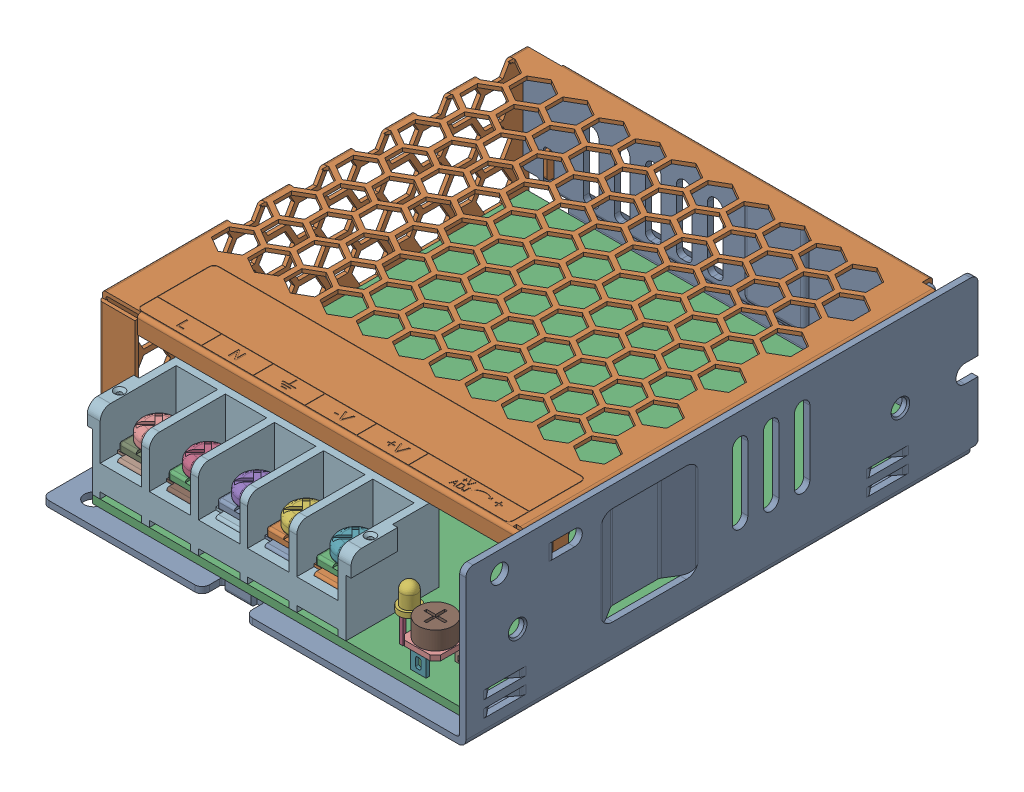
SolidWorks assembly LRS-35,50 Mean Well, configuration Default. Lengths in mm.
Overall size (82 30 99).
4 component instances, 4 part files, 0 mates.
Components (placement in the parent):
- Bot LRS-35,50-1: Bot LRS-35,50 [Default] at origin size (82 30 99)
- Cap LRS-35,50-1: Cap LRS-35,50 [Default] at (0 1.2 -11) size (80.8 28.8 83.2)
- PCB LRS-35,50-1: PCB LRS-35,50 [Default] at (40.8 4.9 -46.5) x (0 0 -1) z (0 1 0) size (93 80 11.5)
- Terminal Block LRS-35,50-1: Terminal Block LRS-35,50 [Default] at (34.3 6.4 -9) size (51 15 18)
